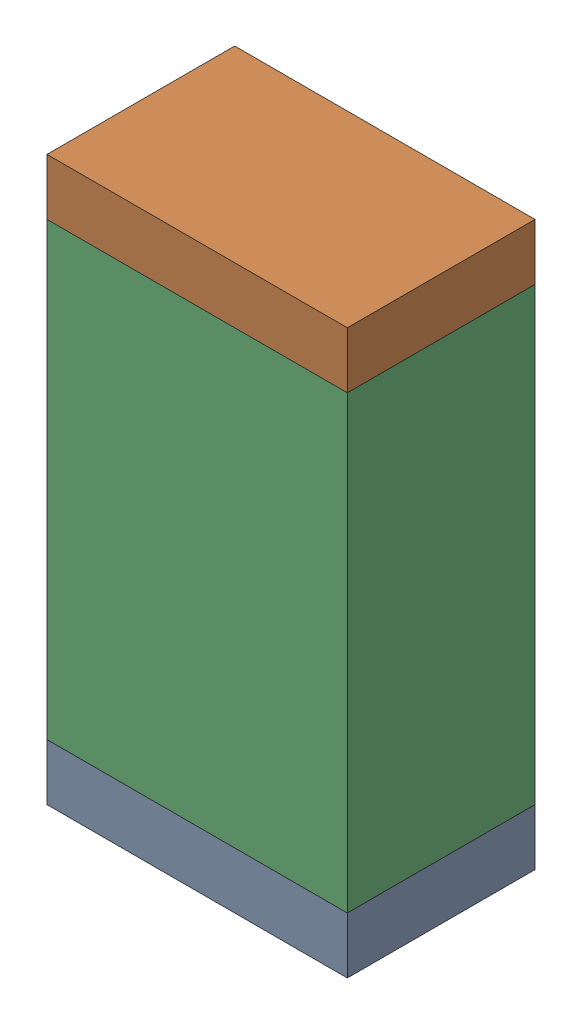
SolidWorks assembly R79, configuration Default. Lengths in mm.
Overall size (0.8 1.5 0.5).
6 component instances, 2 part files, 0 mates.
Components (placement in the parent):
- 810156592-1: 810156592 [Default] at (125.95 20.625 0) size (0.8 0.15 0.5)
  - Extruded_7-1: Extruded_7 [Default] at origin size (0.8 0.15 0.5)
- 810156592-2: 810156592 [Default] at (125.95 21.975 0) size (0.8 0.15 0.5)
  - Extruded_7-1: Extruded_7 [Default] at origin size (0.8 0.15 0.5)
- 810156976-1: 810156976 [Default] at (125.95 21.3 0) size (0.8 1.2 0.5)
  - Extruded_6-1: Extruded_6 [Default] at origin size (0.8 1.2 0.5)
